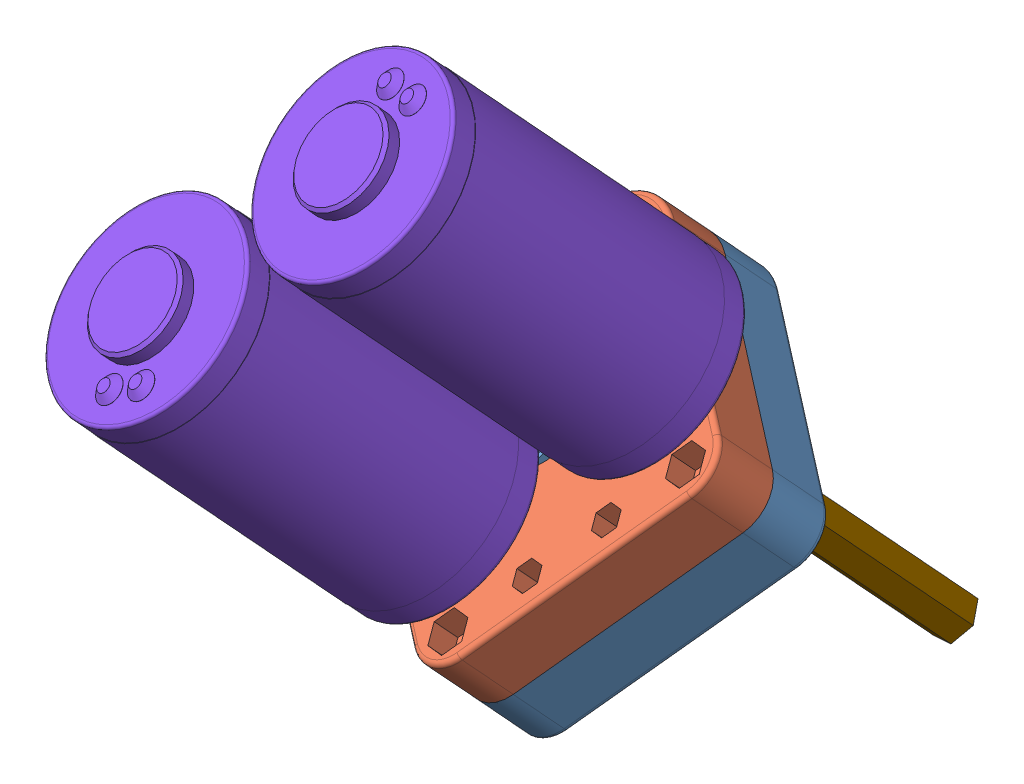
SolidWorks assembly 217-2454-Gearbox with cims, configuration Default. Lengths in mm.
Overall size (162.73 250.89 258.56).
11 component instances, 9 part files, 21 mates.
Components (placement in the parent):
- 217-2454-001 Rev1-1: 217-2454-001 Rev1 [Default] at (147.5037 -53.8894 58.0057) x (-0.545907 -0.661557 0.514128) z (-0.265117 0.718494 0.643023) size (97.79 114.27 23.82)
- 217-2454-002 Rev1-1: 217-2454-002 Rev1 [Default] at (136.561 -24.2335 84.5465) x (0.545907 0.661557 -0.514128) z (0.265117 -0.718494 -0.643023) size (97.79 114.27 24.07)
- 217-2731-1: 217-2731 [Default] at (109.2436 -16.8451 65.0477) x (-0.844778 0.148408 -0.514126) z (-0.464827 -0.679515 0.567622) size (31.12 7.94 31.12)
- 217-2734-1: 217-2734 [Default] at (120.193 -46.5192 38.4905) x (0.963841 0.216079 0.155949) z (0.026895 -0.661117 0.749801) size (31.12 7.94 31.12)
- Grahill Encoder-1: Grahill Encoder [Default] at (99.907 8.4582 87.6931) x (0.893229 -0.068136 0.444409) z (-0.363118 -0.692187 0.623716) size (31.75 31.12 31.75)
- 217-2428-019 Rev1-1: 217-2428-019 Rev1 [Default] at (98.7285 11.6519 90.5513) x (0.545907 0.661557 -0.514128) z (0.265117 -0.718494 -0.643023) size (50.8 19.05 1.57)
- 217-2428-005 Rev1-1: 217-2428-005 Rev1 [Default] at (113.0681 11.133 64.9686) x (0.075372 0.680289 -0.729058) z (0.961266 0.144819 0.234511) size (7.33 38.98 6.35)
- 217-2428-005 Rev1-2: 217-2428-005 Rev1 [Default] at (90.5357 -16.1728 86.1892) x (0.075372 0.680289 -0.729058) z (0.961266 0.144819 0.234511) size (7.33 38.98 6.35)
- 217-2000-1: 217-2000 [Default] at (120.5165 -46.5997 102.9227) x (-0.265117 0.718494 0.643023) z (0.321598 0.694591 -0.64352) size (150.2 64.01 64.01)
- 217-2000-2: 217-2000 [Default] at (156.5497 -2.9329 68.9871) x (-0.265117 0.718494 0.643023) z (-0.733014 -0.58344 0.349698) size (150.2 64.01 64.01)
- Hex Shaft to be Lathed-1: Hex Shaft to be Lathed [Default] at (105.7472 -7.3473 73.5341) x (-0.436617 -0.684054 0.584325) z (0.859697 -0.125841 0.495061) size (14.66 177.48 12.88)
Mates (geometry in assembly coordinates):
- Coincident1: coincident anti-aligned: plane of 217-2454-001 Rev1-1 through (132.0735 -11.7113 36.6098) normal (-0.265117 0.718494 0.643023); plane of 217-2454-002 Rev1-1 through (98.795 -52.0398 67.951) normal (0.265117 -0.718494 -0.643023)
- Coincident2: coincident aligned: plane of 217-2454-001 Rev1-1 through (161.2057 -74.0385 118.2635) normal (0.794794 -0.214727 0.567621); plane of 217-2454-002 Rev1-1 through (201.4172 -25.3082 80.3928) normal (0.794794 -0.214727 0.567621)
- Coincident3: coincident aligned: plane of 217-2454-001 Rev1-1 through (88.7421 -64.2224 77.4187) normal (-0.545907 -0.661557 0.514128); plane of 217-2454-002 Rev1-1 through (145.0301 -79.4295 117.6181) normal (-0.545907 -0.661557 0.514128)
- Concentric1: concentric aligned: cylinder of 217-2454-002 Rev1-1 through (121.1899 -48.4247 101.2894) axis (-0.265117 0.718494 0.643023) radius 9.5504; cylinder of 217-2000-1 through (120.5165 -46.5997 102.9227) axis (-0.265117 0.718494 0.643023) radius 4
- Concentric2: concentric anti-aligned: cylinder of 217-2454-002 Rev1-1 through (108.2322 -74.9616 66.1709) axis (-0.265117 0.718494 0.643023) radius 4.572; cylinder of 217-2000-1 through (97.4278 -45.6806 92.3762) axis (0.265117 -0.718494 -0.643023) radius 2.0193
- Concentric3: concentric aligned: cylinder of 217-2454-002 Rev1-1 through (169.1393 -37.0521 38.4518) axis (-0.265117 0.718494 0.643023) radius 10.0584; cylinder of 217-2000-2 through (156.5497 -2.9329 68.9871) axis (-0.265117 0.718494 0.643023) radius 4
- Concentric4: concentric aligned: cylinder of 217-2454-002 Rev1-1 through (123.5899 -17.3823 39.4486) axis (-0.265117 0.718494 0.643023) radius 2.1526; cylinder of 217-2428-019 Rev1-1 through (108.0176 24.8203 77.2182) axis (-0.265117 0.718494 0.643023) radius 2.1463
- Concentric5: concentric aligned: cylinder of 217-2454-002 Rev1-1 through (123.5899 -17.3823 39.4486) axis (-0.265117 0.718494 0.643023) radius 2.1526; cylinder of 217-2428-005 Rev1-1 through (111.3846 15.6954 69.0518) axis (-0.265117 0.718494 0.643023) radius 2.0955
- Coincident4: coincident anti-aligned: plane of 217-2428-019 Rev1-1 through (129.667 22.8244 88.3743) normal (0.265117 -0.718494 -0.643023); plane of 217-2428-005 Rev1-1 through (104.8274 23.1135 77.8101) normal (-0.265117 0.718494 0.643023)
- Concentric6: concentric aligned: cylinder of Grahill Encoder-1 through (93.8596 24.8473 102.3606) axis (-0.265117 0.718494 0.643023) radius 15.875; cylinder of 217-2428-019 Rev1-1 through (99.146 10.5205 89.5387) axis (-0.265117 0.718494 0.643023) radius 6.35
- Coincident5: coincident anti-aligned: plane of 217-2428-019 Rev1-1 through (129.667 22.8244 88.3743) normal (0.265117 -0.718494 -0.643023); plane of 217-2428-005 Rev1-2 through (82.2951 -4.1923 99.0307) normal (-0.265117 0.718494 0.643023)
- Concentric7: concentric aligned: cylinder of 217-2454-002 Rev1-1 through (101.0576 -44.6881 60.6692) axis (-0.265117 0.718494 0.643023) radius 2.1526; cylinder of 217-2428-005 Rev1-2 through (88.8522 -11.6104 90.2724) axis (-0.265117 0.718494 0.643023) radius 2.0955
- Concentric8: concentric aligned: cylinder of 217-2454-002 Rev1-1 through (101.0576 -44.6881 60.6692) axis (-0.265117 0.718494 0.643023) radius 2.1526; cylinder of 217-2428-019 Rev1-1 through (85.4853 -2.4855 98.4388) axis (-0.265117 0.718494 0.643023) radius 2.1463
- Coincident6: coincident anti-aligned: plane of 217-2454-002 Rev1-1 through (93.3237 -37.2119 81.2214) normal (-0.265117 0.718494 0.643023); plane of 217-2428-005 Rev1-2 through (92.396 -31.567 74.5315) normal (0.265117 -0.718494 -0.643023)
- Coincident7: coincident anti-aligned: plane of 217-2454-002 Rev1-1 through (93.3237 -37.2119 81.2214) normal (-0.265117 0.718494 0.643023); plane of 217-2000-2 through (150.583 0.6736 62.4973) normal (0.265117 -0.718494 -0.643023)
- Coincident8: coincident anti-aligned: plane of 217-2454-002 Rev1-1 through (93.3237 -37.2119 81.2214) normal (-0.265117 0.718494 0.643023); plane of 217-2000-1 through (129.1747 -46.9444 106.8776) normal (0.265117 -0.718494 -0.643023)
- Concentric10: concentric anti-aligned: cylinder of 217-2454-002 Rev1-1 through (109.9204 -18.6792 63.4062) axis (-0.265117 0.718494 0.643023) radius 14.2875; cylinder of 217-2731-1 through (109.2436 -16.8451 65.0477) axis (0.265117 -0.718494 -0.643023) radius 14.2875
- Coincident13: coincident anti-aligned: plane of 217-2454-002 Rev1-1 through (110.9271 -21.4075 60.9645) normal (0.265117 -0.718494 -0.643023); plane of 217-2731-1 through (97.7845 -19.0986 52.9659) normal (-0.265117 0.718494 0.643023)
- Concentric12: concentric anti-aligned: cylinder of 217-2454-001 Rev1-1 through (119.5163 -44.6851 40.132) axis (0.265117 -0.718494 -0.643023) radius 14.2875; cylinder of 217-2734-1 through (120.193 -46.5192 38.4905) axis (-0.265117 0.718494 0.643023) radius 14.2748
- Coincident15: coincident anti-aligned: plane of 217-2454-001 Rev1-1 through (118.5095 -41.9567 42.5737) normal (-0.265117 0.718494 0.643023); plane of 217-2734-1 through (133.5045 -38.5951 44.9999) normal (0.265117 -0.718494 -0.643023)
- Coincident18: coincident anti-aligned: plane of Grahill Encoder-1 through (96.4227 7.2566 94.5119) normal (0.265117 -0.718494 -0.643023); plane of 217-2428-019 Rev1-1 through (129.2495 23.9559 89.387) normal (-0.265117 0.718494 0.643023)
